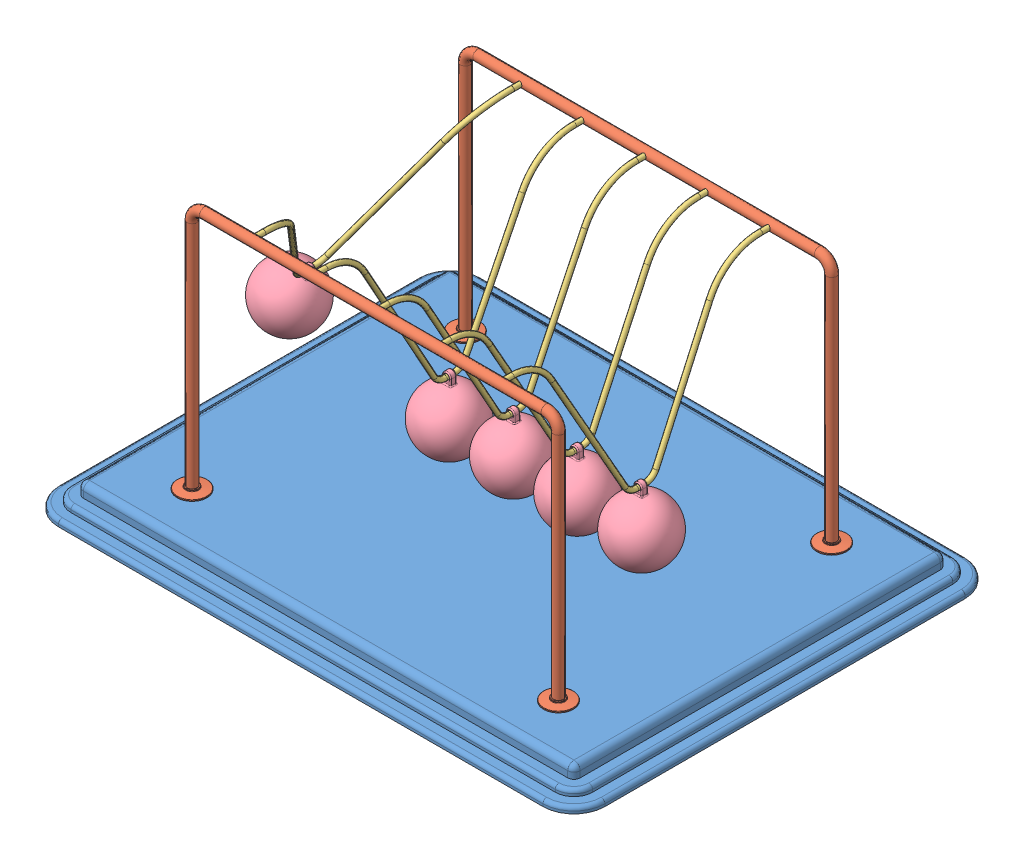
SolidWorks assembly Newtons Cradle NewtonsCradle 0241, configuration Default. Lengths in mm.
Overall size (440 222 340).
13 component instances, 4 part files, 34 mates.
Components (placement in the parent):
- Base NewtonsCradle 0241-1: Base NewtonsCradle 0241 [Default] at (-16.2968 -4.1587 11.425) size (440 20 340)
- frame NewtonsCradle 0241-1: frame NewtonsCradle 0241 [Default] at (-16.2968 144.4547 -98.575) size (319 202 24)
- frame NewtonsCradle 0241-2: frame NewtonsCradle 0241 [Default] at (-16.2968 144.4547 121.425) x (-1 0 0) z (0 0 -1) size (319 202 24)
- Hanging thing NewtonsCradle 0241-1: Hanging thing NewtonsCradle 0241 [Default] at (-157.6326 134.1825 11.425) x (0 0 1) z (-0.859985 0.510319 0) size (220 129 4)
- Hanging thing NewtonsCradle 0241-2: Hanging thing NewtonsCradle 0241 [Default] at (-66.576 122.8418 11.425) x (0 0 1) z (-0.999994 0.003446 0) size (220 129 4)
- Hanging thing NewtonsCradle 0241-3: Hanging thing NewtonsCradle 0241 [Default] at (-15.6923 122.8436 11.425) x (0 0 1) z (-0.999972 -0.007464 0) size (220 129 4)
- Hanging thing NewtonsCradle 0241-4: Hanging thing NewtonsCradle 0241 [Default] at (35.2213 122.8555 11.425) x (0 0 1) z (-0.999824 -0.018742 0) size (220 129 4)
- Hanging thing NewtonsCradle 0241-5: Hanging thing NewtonsCradle 0241 [Default] at (86.0287 122.8747 11.425) x (0 0 1) z (-0.999588 -0.028711 0) size (220 129 4)
- Sphere NewtonsCradle 0241-1: Sphere NewtonsCradle 0241 [Default] at (-195.3962 70.5436 11.425) x (0.859985 -0.510319 0) z (0 0 1) size (50 58.5 50)
- Sphere NewtonsCradle 0241-2: Sphere NewtonsCradle 0241 [Default] at (88.1533 48.9052 11.425) x (0.999588 0.028711 0) z (0 0 1) size (50 58.5 50)
- Sphere NewtonsCradle 0241-3: Sphere NewtonsCradle 0241 [Default] at (-15.14 48.8456 11.425) x (0.999972 0.007464 0) z (0 0 1) size (50 58.5 50)
- Sphere NewtonsCradle 0241-4: Sphere NewtonsCradle 0241 [Default] at (36.6081 48.8685 11.425) x (0.999824 0.018742 0) z (0 0 1) size (50 58.5 50)
- Sphere NewtonsCradle 0241-5: Sphere NewtonsCradle 0241 [Default] at (-66.831 48.8422 11.425) x (0.999994 -0.003446 0) z (0 0 1) size (50 58.5 50)
Mates (geometry in assembly coordinates):
- Coincident1: coincident anti-aligned: plane of Base-1 through (-211.2968 5.8413 156.425) normal (0 1 0); plane of frame-2 through (-175.7968 5.8413 121.425) normal (0 -1 0)
- Coincident2: coincident anti-aligned: plane of Base-1 through (-211.2968 5.8413 156.425) normal (0 1 0); plane of frame-1 through (143.2032 5.8413 -98.575) normal (0 -1 0)
- Concentric1: concentric anti-aligned: cylinder of frame-1 through (-116.2968 203.8413 -94.575) axis (0 0 -1) radius 2; cylinder of frame-2 through (-116.2968 203.8413 117.425) axis (0 0 1) radius 2
- Concentric2: concentric anti-aligned: cylinder of frame-1 through (83.7032 203.8413 -94.575) axis (0 0 -1) radius 2; cylinder of frame-2 through (83.7032 203.8413 117.425) axis (0 0 1) radius 2
- Distance1: distance = 60 mm: plane of frame-1 through (-16.2968 144.4547 -98.575) normal (0 0 1); line of Base-1 through (-211.2968 -12.1587 -158.575) axis (1 0 0)
- Distance2: distance = 60 mm: line of Base-1 through (178.7032 -12.1587 181.425) axis (-1 0 0); plane of frame-2 through (-16.2968 144.4547 121.425) normal (0 0 -1)
- Distance3: distance = 220 mm: plane of frame-2 through (-16.2968 144.4547 121.425) normal (-1 0 0); line of Base-1 through (-236.2968 -12.1587 156.425) axis (0 0 -1)
- Concentric3: concentric anti-aligned: cylinder of frame-1 through (-116.2968 203.8413 -94.575) axis (0 0 -1) radius 2; cylinder of Hanging thing-1 through (-116.2968 203.8413 111.425) axis (0 0 1) radius 2
- Concentric4: concentric anti-aligned: cylinder of frame-1 through (-116.2968 203.8413 -94.575) axis (0 0 -1) radius 2; cylinder of Hanging thing-1 through (-116.2968 203.8413 -98.575) axis (0 0 1) radius 2
- Concentric5: concentric aligned: cylinder of frame-2 through (-66.2968 203.8413 117.425) axis (0 0 1) radius 2; cylinder of Hanging thing-2 through (-66.2968 203.8413 111.425) axis (0 0 1) radius 2
- Concentric6: concentric aligned: cylinder of frame-2 through (-16.2968 203.8413 117.425) axis (0 0 1) radius 2; cylinder of Hanging thing-3 through (-16.2968 203.8413 111.425) axis (0 0 1) radius 2
- Concentric7: concentric aligned: cylinder of frame-2 through (33.7032 203.8413 117.425) axis (0 0 1) radius 2; cylinder of Hanging thing-4 through (33.7032 203.8413 111.425) axis (0 0 1) radius 2
- Concentric8: concentric aligned: cylinder of frame-2 through (83.7032 203.8413 117.425) axis (0 0 1) radius 2; cylinder of Hanging thing-5 through (83.7032 203.8413 111.425) axis (0 0 1) radius 2
- Coincident5: coincident anti-aligned: plane of frame-2 through (83.7032 203.8413 121.425) normal (0 0 -1); plane of Hanging thing-5 through (83.7032 203.8413 121.425) normal (0 0 1)
- Coincident6: coincident anti-aligned: plane of frame-2 through (33.7032 203.8413 121.425) normal (0 0 -1); plane of Hanging thing-4 through (33.7032 203.8413 121.425) normal (0 0 1)
- Coincident7: coincident anti-aligned: plane of frame-2 through (-16.2968 203.8413 121.425) normal (0 0 -1); plane of Hanging thing-3 through (-16.2968 203.8413 121.425) normal (0 0 1)
- Coincident8: coincident anti-aligned: plane of frame-2 through (-66.2968 203.8413 121.425) normal (0 0 -1); plane of Hanging thing-2 through (-66.2968 203.8413 121.425) normal (0 0 1)
- Coincident9: coincident anti-aligned: plane of frame-2 through (-116.2968 203.8413 121.425) normal (0 0 -1); plane of Hanging thing-1 through (-116.2968 203.8413 121.425) normal (0 0 1)
- Concentric9: concentric anti-aligned: cylinder of Hanging thing-1 through (-117.0163 78.8434 7.925) axis (0 0 1) radius 2; cylinder of Sphere-1 through (-117.0163 78.8434 13.925) axis (0 0 -1) radius 2
- Concentric13: concentric anti-aligned: cylinder of Hanging thing-2 through (-66.7276 78.842 7.925) axis (0 0 1) radius 2; cylinder of Sphere-5 through (-66.7276 78.842 13.925) axis (0 0 -1) radius 2
- Concentric15: concentric anti-aligned: cylinder of Hanging thing-3 through (-15.3639 78.8448 7.925) axis (0 0 1) radius 2; cylinder of Sphere-3 through (-15.3639 78.8448 13.925) axis (0 0 -1) radius 2
- Concentric16: concentric anti-aligned: cylinder of Hanging thing-5 through (87.292 78.8928 7.925) axis (0 0 1) radius 2; cylinder of Sphere-2 through (87.292 78.8928 13.925) axis (0 0 -1) radius 2
- Concentric17: concentric anti-aligned: cylinder of Hanging thing-4 through (36.0459 78.8632 7.925) axis (0 0 1) radius 2; cylinder of Sphere-4 through (36.0459 78.8632 13.925) axis (0 0 -1) radius 2
- Parallel1: parallel anti-aligned: plane of Hanging thing-1; plane of Sphere-1
- Coincident22: coincident anti-aligned: plane of Hanging thing-1; plane of Sphere-1
- Coincident12: coincident aligned: plane of Hanging thing-2 through (-66.576 122.8418 11.425) normal (0 0 1); plane of Sphere-5 through (-66.831 48.8422 11.425) normal (0 0 1)
- Coincident10: coincident aligned: plane of Hanging thing-1 through (-116.763 122.8426 11.425) normal (0 0 1); plane of Sphere-1 through (-118.5806 48.8842 11.425) normal (0 0 1)
- Coincident13: coincident anti-aligned: plane of Hanging thing-2 through (-66.576 122.8418 11.425) normal (-0.999994 0.003446 0); plane of Sphere-5 through (-66.831 48.8422 11.425) normal (0.999994 -0.003446 0)
- Coincident14: coincident anti-aligned: plane of Hanging thing-3 through (-15.6923 122.8436 11.425) normal (-0.999972 -0.007464 0); plane of Sphere-3 through (-15.14 48.8456 11.425) normal (0.999972 0.007464 0)
- Coincident15: coincident aligned: plane of Hanging thing-3 through (-15.6923 122.8436 11.425) normal (0 0 1); plane of Sphere-3 through (-15.14 48.8456 11.425) normal (0 0 1)
- Coincident18: coincident aligned: plane of Hanging thing-4 through (35.2213 122.8555 11.425) normal (0 0 1); plane of Sphere-4 through (36.6081 48.8685 11.425) normal (0 0 1)
- Coincident19: coincident anti-aligned: plane of Hanging thing-4 through (35.2213 122.8555 11.425) normal (-0.999824 -0.018742 0); plane of Sphere-4 through (36.6081 48.8685 11.425) normal (0.999824 0.018742 0)
- Coincident20: coincident anti-aligned: plane of Hanging thing-5 through (86.0287 122.8747 11.425) normal (-0.999588 -0.028711 0); plane of Sphere-2 through (88.1533 48.9052 11.425) normal (0.999588 0.028711 0)
- Coincident21: coincident aligned: plane of Hanging thing-5 through (86.0287 122.8747 11.425) normal (0 0 1); plane of Sphere-2 through (88.1533 48.9052 11.425) normal (0 0 1)
